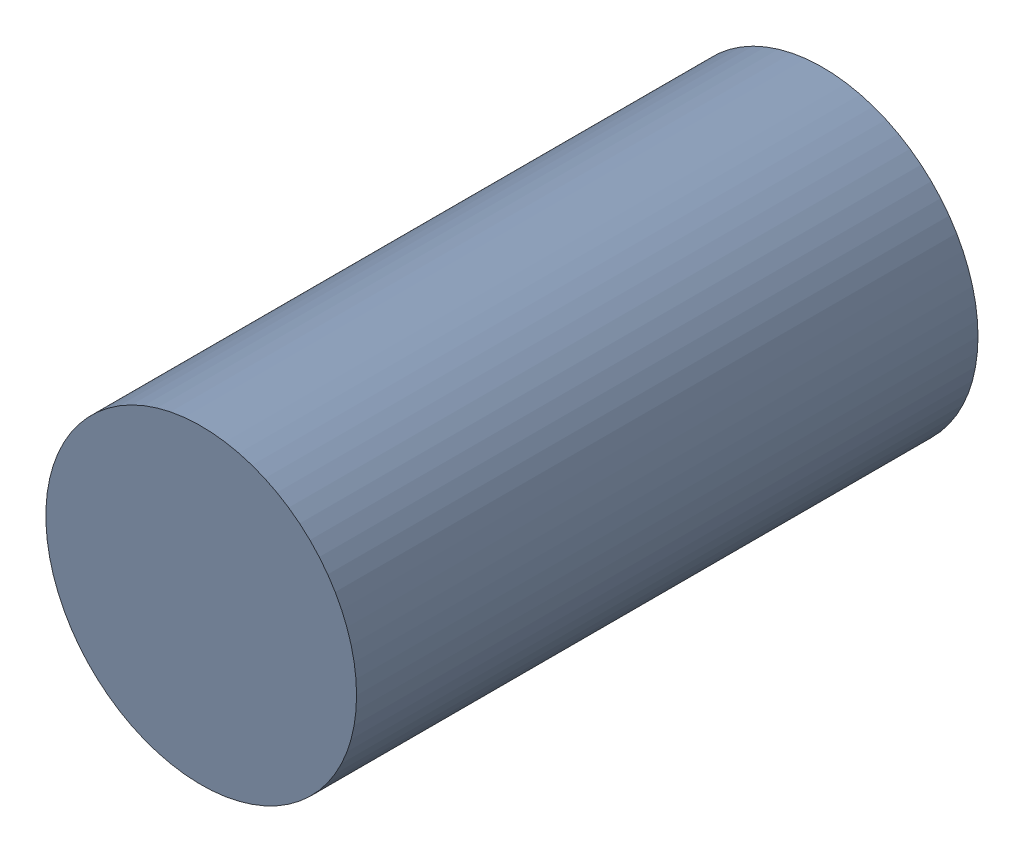
SolidWorks assembly MH11_1.step, configuration Default. Lengths in mm.
Overall size (1 1 2).
2 component instances, 1 part files, 0 mates.
Components (placement in the parent):
- 9228463120_1.step-3: 9228463120_1.step [Default] at (453.1614 297.4086 -1.5) size (1 1 2)
  - Cylinder_1.step-26: Cylinder_1.step [Default] at origin size (1 1 2)
